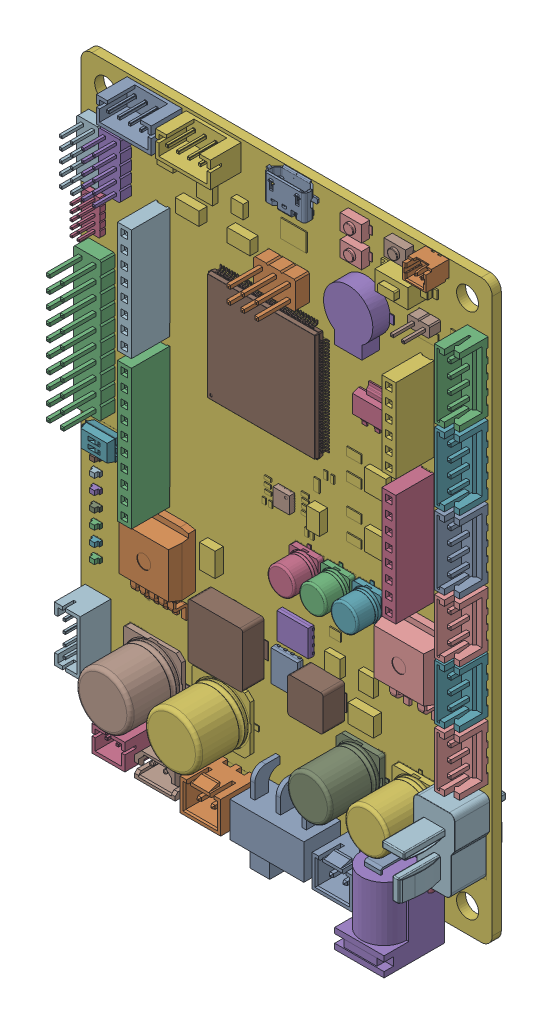
SolidWorks assembly OpenCR_REV0_LC.step, configuration Défaut. Lengths in mm.
Overall size (75 109 19.36).
77 component instances, 52 part files, 0 mates.
Components (placement in the parent):
- JST_B4B_EH_A.step-1: JST_B4B_EH_A.step [Default] at (35.5087 5.7679 0) x (0 1 0) z (0 0 1) size (12.5 3.8 9.2)
- TO_263_5_TabPin3.step-1: TO_263_5_TabPin3.step [Défaut] at (-20.6929 -22.2686 -0.02) x (0 1 0) z (0 0 1) size (15 10 4.42)
- LED_0603_1608Metric.step-1: LED_0603_1608Metric.step [Défaut] at (-33.4491 -22.864 0) size (1.6 0.8 1.1)
- Part 1.step-1: Part 1.step [Défaut] at (-25.9491 -51.2031 0) x (-1 0 0) z (0 0 1) size (6 4.7 9.7)
- Part 1-0.step-1: Part 1-0.step [Défaut] at (3.0469 -21.7642 0) size (6 4.9 1)
- CP_Elec_10x10.step-1: CP_Elec_10x10.step [Défaut] at (-10.0103 -40.6477 0) x (-1 0 0) z (0 0 1) size (12 10.3 10)
- JST_B3B_EH_A.step-1: JST_B3B_EH_A.step [Défaut] at (35.5087 -15.3304 0) x (0 1 0) z (0 0 1) size (10 3.8 9.2)
- QFN-24_3x3mm_Pitch0.4mm.step-1: QFN-24_3x3mm_Pitch0.4mm.step [Défaut] at (0.9632 -1.6528 0) x (0 -1 0) z (0 0 1) size (3 3 1.02)
- LED_0603_1608Metric.step-2: LED_0603_1608Metric.step [Défaut] at (-33.4491 -20.1713 0) size (1.6 0.8 1.1)
- JST_B3B_EH_A.step-2: JST_B3B_EH_A.step [Défaut] at (35.5087 -4.9765 0) x (0 1 0) z (0 0 1) size (10 3.8 9.2)
- Part 1-1.step-1: Part 1-1.step [Défaut] at (8.3795 -28.6124 0.1) x (0 -1 0) z (0 0 1) size (6.5 7.1 4)
- Part 1-2.step-1: Part 1-2.step [Défaut] at (-34.0323 -38.693 0) x (0 -1 0) z (0 0 1) size (10 4.7 9.1)
- Part 1-3.step-1: Part 1-3.step [Défaut] at (-2.7022 -54.1531 0) size (13.5 15.1 8.6)
- SMW250-02_P2-5_L7-4_W5-8_H7.step-1: SMW250-02_P2-5_L7-4_W5-8_H7.step [Défaut] at (-7.7904 -51.2531 0) x (-1 0 0) z (0 1 0) size (7.4 10.5 6.39)
- CP_Elec_5x53.step-1: CP_Elec_5x53.step [Défaut] at (10.9372 -10.1709 0) x (0 1 0) z (0 0 1) size (6.5 5.3 5.3)
- LM1117.step-1: LM1117.step [Défaut] at (14.3585 18.9457 0.3) x (1 0 0) z (0 -1 0) size (6.7 1.7 7.32)
- Part 1-4.step-1: Part 1-4.step [Défaut] at (15.374 36.1915 0) size (10.5 10.6 3.2)
- CP_Elec_8x10.step-1: CP_Elec_8x10.step [Défaut] at (25.44 -37.151 0) x (0 1 0) z (0 0 1) size (9.5 8.3 10)
- JST_B4B_EH_A.step-2: JST_B4B_EH_A.step [Default] at (35.5087 18.9498 0) x (0 1 0) z (0 0 1) size (12.5 3.8 9.2)
- PinHeader_1x02_P200mm_Vertical.step-1: PinHeader_1x02_P200mm_Vertical.step [Défaut] at (28.0338 39.4207 0) x (0 -1 0) z (0 0 1) size (2 4 8.8)
- SOIC_8_39x49mm_P127mm.step-1: SOIC_8_39x49mm_P127mm.step [Défaut] at (-25.2827 -37.9183 -1.55) x (-1 0 0) z (0 0 -1) size (6 4.9 1.75)
- Part 1-5.step-1: Part 1-5.step [Défaut] at (14.1589 48.2947 0) size (4.9 2.9 2)
- Part 1-6.step-1: Part 1-6.step [Défaut] at (-8.0698 -27.5475 0.1) x (0 1 0) z (0 0 1) size (10 11.5 4)
- PinSocket_1x08_P254mm_Vertical.step-1: PinSocket_1x08_P254mm_Vertical.step [Défaut] at (-21.6267 14.3888 0) x (-1 0 0) z (0 0 1) size (2.54 20.32 10.1)
- CUI_PJ-102A.step-1: CUI_PJ-102A.step [Défaut] at (25.2172 -49.2646 0) x (-1 0 0) z (0 1 0) size (3 12.1 2.38)
- 530470210.step-1: 530470210.step [Défaut] at (28.4252 49.1692 3.225) x (-1 0 0) z (0 1 0) size (4.25 6.5 3.2)
- PinSocket_1x10_P254mm_Vertical.step-1: PinSocket_1x10_P254mm_Vertical.step [Défaut] at (-21.6296 -12.5262 0) x (-1 0 0) z (0 0 1) size (2.54 25.4 10.1)
- CP_Elec_5x53.step-2: CP_Elec_5x53.step [Défaut] at (5.175 -10.181 0) x (0 1 0) z (0 0 1) size (6.5 5.3 5.3)
- LED_0603_1608Metric.step-3: LED_0603_1608Metric.step [Défaut] at (-33.4491 -17.3888 0) size (1.6 0.8 1.1)
- Part 1-2.step-2: Part 1-2.step [Défaut] at (-12.3505 48.5266 0) x (-1 0 0) z (0 0 1) size (10 4.7 9.1)
- SW_DIP_SPSTx02_Slide_Copal_CHS_02B_W762mm_P127mm.step-1: SW_DIP_SPSTx02_Slide_Copal_CHS_02B_W762mm_P127mm.step [Défaut] at (-31.661 -8.5258 -0.1) size (8 3.77 2.58)
- CP_Elec_10x10.step-2: CP_Elec_10x10.step [Défaut] at (-22.5119 -40.6477 0) x (-1 0 0) z (0 0 1) size (12 10.3 10)
- CUI_PJ-102A-7.step-1: CUI_PJ-102A-7.step [Défaut] at (24.9673 -49.94 0) x (-1 0 0) z (0 1 0) size (2 11 6.25)
- JST_B3B_EH_A.step-3: JST_B3B_EH_A.step [Défaut] at (35.5087 -26.0076 0) x (0 1 0) z (0 0 1) size (10 3.8 9.2)
- HTSSOP_28_1EP_44x97mm_P065mm.step-1: HTSSOP_28_1EP_44x97mm_P065mm.step [Défaut] at (8.9013 -15.9661 -1.65) x (0 -1 0) z (0 0 -1) size (6.4 9.7 1.2)
- LED_0603_1608Metric.step-4: LED_0603_1608Metric.step [Défaut] at (-33.4491 -14.6568 0) size (1.6 0.8 1.1)
- SMW250-02_P2-5_L7-4_W5-8_H7.step-2: SMW250-02_P2-5_L7-4_W5-8_H7.step [Défaut] at (16.2963 -51.2531 0) x (-1 0 0) z (0 1 0) size (7.4 10.5 6.39)
- PinHeader_2x03_P254mm_Vertical.step-1: PinHeader_2x03_P254mm_Vertical.step [Défaut] at (-1.2405 32.2476 0) x (0 1 0) z (0 0 1) size (5.08 7.62 11.54)
- PinHeader_2x10_P254mm_Vertical.step-1: PinHeader_2x10_P254mm_Vertical.step [Défaut] at (-34.1449 20.0493 0) size (5.08 25.4 11.54)
- PinHeader_2x05_P127mm_Vertical.step-1: PinHeader_2x05_P127mm_Vertical.step [Défaut] at (-34.4284 28.949 0) size (3.4 6.35 6.3)
- PinHeader_2x05_P200mm_Vertical.step-1: PinHeader_2x05_P200mm_Vertical.step [Défaut] at (-30.3572 40.6493 0) size (4 10 8.8)
- Part 1-8.step-1: Part 1-8.step [Défaut] at (23.5594 44.2809 0) x (0 -1 0) z (0 0 1) size (3.5 10.2 4.5)
- USB_Micro-B_Molex_47346-0001.step-1: USB_Micro-B_Molex_47346-0001.step [Défaut] at (2.9806 46.998 0.0143) x (-1 0 0) z (0 0 1) size (0.26 0.6 0.01)
- USB_Micro-B_Molex_47346-0001-9.step-1: USB_Micro-B_Molex_47346-0001-9.step [Défaut] at (2.9806 46.998 0.0143) x (-1 0 0) z (0 0 1) size (0.01 0.77 0.15)
- USB_Micro-B_Molex_47346-0001-10.step-1: USB_Micro-B_Molex_47346-0001-10.step [Défaut] at (2.9806 46.998 0.0143) x (-1 0 0) z (0 0 1) size (3.83 0.01 0.4)
- USB_Micro-B_Molex_47346-0001-11.step-1: USB_Micro-B_Molex_47346-0001-11.step [Défaut] at (2.9806 46.998 0.0143) x (-1 0 0) z (0 0 1) size (7.99 5.43 2.95)
- USB_Micro-B_Molex_47346-0001-12.step-1: USB_Micro-B_Molex_47346-0001-12.step [Défaut] at (2.9806 46.998 0.0143) x (-1 0 0) z (0 0 1) size (0.26 0.6 0.01)
- USB_Micro-B_Molex_47346-0001-13.step-1: USB_Micro-B_Molex_47346-0001-13.step [Défaut] at (2.9806 46.998 0.0143) x (-1 0 0) z (0 0 1) size (0.26 0.6 0.01)
- USB_Micro-B_Molex_47346-0001-14.step-1: USB_Micro-B_Molex_47346-0001-14.step [Défaut] at (2.9806 46.998 0.0143) x (-1 0 0) z (0 0 1) size (0.26 0.6 0.01)
- USB_Micro-B_Molex_47346-0001-15.step-1: USB_Micro-B_Molex_47346-0001-15.step [Défaut] at (2.9806 46.998 0.0143) x (-1 0 0) z (0 0 1) size (3.55 0.65 0.02)
- USB_Micro-B_Molex_47346-0001-16.step-1: USB_Micro-B_Molex_47346-0001-16.step [Défaut] at (2.9806 46.998 0.0143) x (-1 0 0) z (0 0 1) size (0.26 0.6 0.01)
- Part 1-17.step-1: Part 1-17.step [Défaut] at (16.9581 -46.3096 -1.65) x (1 0 0) z (0 0 -1) size (9.73 5.03 3.81)
- Part 1-5.step-2: Part 1-5.step [Défaut] at (22.1785 48.3041 0) size (4.9 2.9 2)
- SOT_223.step-1: SOT_223.step [Défaut] at (-21.0916 -44.8278 -1.55) x (-1 0 0) z (0 0 -1) size (7 6.5 1.7)
- Part 1-5.step-3: Part 1-5.step [Défaut] at (14.1589 44.0757 0) size (4.9 2.9 2)
- LED_0603_1608Metric.step-5: LED_0603_1608Metric.step [Défaut] at (-33.4491 -12.1667 0) size (1.6 0.8 1.1)
- PinHeader_2x05_P200mm_Vertical.step-2: PinHeader_2x05_P200mm_Vertical.step [Défaut] at (-34.3385 40.6493 0) size (4 10 8.8)
- Part 1-2.step-3: Part 1-2.step [Défaut] at (-23.1376 48.5266 0) x (-1 0 0) z (0 0 1) size (10 4.7 9.1)
- SOT_223.step-2: SOT_223.step [Défaut] at (-12.5749 -4.1062 -1.55) x (0 1 0) z (0 0 -1) size (7 6.5 1.7)
- JST_B4B_EH_A.step-3: JST_B4B_EH_A.step [Default] at (35.5087 32.1277 0) x (0 1 0) z (0 0 1) size (12.5 3.8 9.2)
- PinSocket_1x08_P254mm_Vertical.step-2: PinSocket_1x08_P254mm_Vertical.step [Défaut] at (26.5869 -3.4167 0) x (-1 0 0) z (0 0 1) size (2.54 20.32 10.1)
- CUI_PJ-102A-18.step-1: CUI_PJ-102A-18.step [Défaut] at (25.2172 -49.94 0) x (-1 0 0) z (0 1 0) size (9 11 14.4)
- Part 1-19.step-1: Part 1-19.step [Défaut] at (0.9446 -1.6531 -1.65) x (0 1 0) z (0 0 1) size (105 75 4.35)
- CP_Elec_5x53.step-3: CP_Elec_5x53.step [Défaut] at (16.6711 -10.1704 0) x (0 1 0) z (0 0 1) size (6.5 5.3 5.3)
- 022035025.step-1: 022035025.step [Défaut] at (-17.2717 -51.4942 2.85) x (1 0 0) z (0 -1 0) size (7.4 9.4 4.9)
- CP_Elec_8x10.step-2: CP_Elec_8x10.step [Défaut] at (14.9287 -37.1453 0) size (9.5 8.3 10)
- TO_263_2.step-1: TO_263_2.step [Défaut] at (25.8176 -15.4547 -0.02) x (0 1 0) z (0 0 1) size (15 10 4.42)
- LQFP_144_20x20mm_P05mm.step-1: LQFP_144_20x20mm_P05mm.step [Défaut] at (-2.2043 18.1972 0) x (0 1 0) z (0 0 1) size (22 22 1.5)
- Part 1-20.step-1: Part 1-20.step [Défaut] at (34.2415 -37.0026 3.2) size (7.5 13.6 18.9)
- Part 1-0.step-2: Part 1-0.step [Défaut] at (1.5121 -28.6107 0) x (0 -1 0) z (0 0 1) size (6 4.9 1)
- TO_252_2.step-1: TO_252_2.step [Défaut] at (27.3431 -32.4965 -1.63) x (0 -1 0) z (0 0 -1) size (9.9 6.5 2.32)
- LED_0603_1608Metric.step-6: LED_0603_1608Metric.step [Défaut] at (-33.4491 -28.2877 0) size (1.6 0.8 1.1)
- CUI_PJ-102A-21.step-1: CUI_PJ-102A-21.step [Défaut] at (25.2172 -49.94 0) x (-1 0 0) z (0 1 0) size (2.4 6.5 2.5)
- SOIC_8_39x49mm_P127mm.step-2: SOIC_8_39x49mm_P127mm.step [Défaut] at (19.7935 28.4943 -1.55) x (0 1 0) z (0 0 -1) size (6 4.9 1.75)
- PinSocket_1x06_P254mm_Vertical.step-1: PinSocket_1x06_P254mm_Vertical.step [Défaut] at (26.5808 32.1509 0) size (2.54 15.24 10.1)
- LED_0603_1608Metric.step-7: LED_0603_1608Metric.step [Défaut] at (-33.4491 -25.6162 0) size (1.6 0.8 1.1)
- LM1117.step-2: LM1117.step [Défaut] at (-7.4914 -37.7893 -1.95) x (0 -1 0) z (1 0 0) size (6.7 1.7 7.32)
